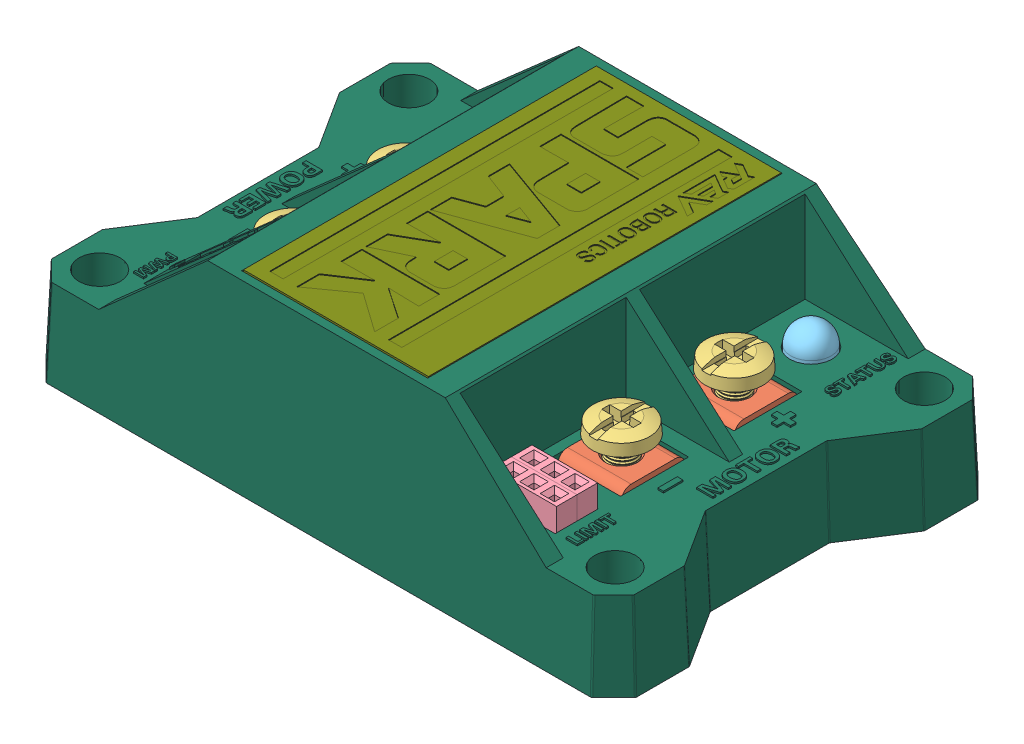
SolidWorks assembly REV-11-1200, configuration Default. Lengths in mm.
Overall size (73.01 27.38 47.86).
37 component instances, 17 part files, 0 mates.
Components (placement in the parent):
- REV_SPARK-1: REV_SPARK [Default] at (-30.2194 -29.0303 -50.3438) size (73.01 27.38 47.86)
  - RR-SPARK-BD-B-Assembly-1: RR-SPARK-BD-B-Assembly [Default] at (2.3249 6.4587 12.2534) size (55.12 26.11 42.42)
    - RR-SPARK-BD-B-1: RR-SPARK-BD-B [Default] at (27.8945 25.8332 38.0904) size (53.34 3.8 40.64)
    - ScrewTerminalAssembly-1: ScrewTerminalAssembly [Default] at (15.7541 22.7195 39.4261) x (0 0 1) z (-1 0 0) size (7.87 11.69 7.87)
      - ScrewTerminalBase-1: ScrewTerminalBase [Default] at (3.4868 6.6312 8.3972) size (7.87 7.68 7.87)
      - ScrewTerminalScrew-1: ScrewTerminalScrew [Default] at (3.5041 -1.1314 8.5263) x (0.998152 0 -0.060771) z (0.060771 0 0.998152) size (7.16 8.3 7.16)
    - ScrewTerminalAssembly-2: ScrewTerminalAssembly [Default] at (56.3941 22.7195 39.4261) x (0 0 1) z (-1 0 0) size (7.87 11.69 7.87)
      - ScrewTerminalBase-1: ScrewTerminalBase [Default] at (3.4868 6.6312 8.3972) size (7.87 7.68 7.87)
      - ScrewTerminalScrew-1: ScrewTerminalScrew [Default] at (3.5041 -1.1314 8.5263) x (0.998152 0 -0.060771) z (0.060771 0 0.998152) size (7.16 8.3 7.16)
    - ScrewTerminalAssembly-3: ScrewTerminalAssembly [Default] at (15.7541 22.7195 25.4561) x (0 0 1) z (-1 0 0) size (7.87 11.69 7.87)
      - ScrewTerminalBase-1: ScrewTerminalBase [Default] at (3.4868 6.6312 8.3972) size (7.87 7.68 7.87)
      - ScrewTerminalScrew-1: ScrewTerminalScrew [Default] at (3.5041 -1.1314 8.5263) x (0.998152 0 -0.060771) z (0.060771 0 0.998152) size (7.16 8.3 7.16)
    - ScrewTerminalAssembly-4: ScrewTerminalAssembly [Default] at (56.3941 22.7195 25.4561) x (0 0 1) z (-1 0 0) size (7.87 11.69 7.87)
      - ScrewTerminalBase-1: ScrewTerminalBase [Default] at (3.4868 6.6312 8.3972) size (7.87 7.68 7.87)
      - ScrewTerminalScrew-1: ScrewTerminalScrew [Default] at (3.5041 -1.1314 8.5263) x (0.998152 0 -0.060771) z (0.060771 0 0.998152) size (7.16 8.3 7.16)
    - Header-Female-1x3-PPTC031LFBN-RC-1: Header-Female-1x3-PPTC031LFBN-RC [Default] at (7.5745 27.4332 53.3304) size (8.13 15.71 2.54)
    - Header-Female-1x3-PPTC031LFBN-RC-2: Header-Female-1x3-PPTC031LFBN-RC [Default] at (48.2145 27.4332 53.3304) size (8.13 15.71 2.54)
    - Header-Female-1x3-PPTC031LFBN-RC-3: Header-Female-1x3-PPTC031LFBN-RC [Default] at (48.2145 27.4332 55.8704) size (8.13 15.71 2.54)
    - LED-RGB-ThroughHole-1: LED-RGB-ThroughHole [Default] at (48.2145 27.4332 21.5804) x (-1 0 0) z (0 0 -1) size (5.45 12.2 5.9)
    - MOSFET-PSMN1R0-30YLC115-1: MOSFET-PSMN1R0-30YLC115 [Default] at (35.6415 27.4332 27.2954) x (0 0 -1) z (1 0 0) size (5 1.2 6.72)
    - MOSFET-PSMN1R0-30YLC115-2: MOSFET-PSMN1R0-30YLC115 [Default] at (36.5305 27.4332 33.6454) size (5 1.2 6.72)
    - MOSFET-PSMN1R0-30YLC115-3: MOSFET-PSMN1R0-30YLC115 [Default] at (36.5305 27.4332 42.5354) x (-1 0 0) z (0 0 -1) size (5 1.2 6.72)
    - MOSFET-PSMN1R0-30YLC115-4: MOSFET-PSMN1R0-30YLC115 [Default] at (35.6415 27.4332 48.8854) x (0 0 -1) z (1 0 0) size (5 1.2 6.72)
    - Varistor-1: Varistor [Default] at (52.6595 27.4332 22.5964) x (0 0 1) z (-1 0 0) size (3.4 1.02 1.45)
    - Varistor-2: Varistor [Default] at (41.2295 27.4332 53.7114) x (0 0 1) z (-1 0 0) size (3.4 1.02 1.45)
    - Crystal-1: Crystal [Default] at (17.9885 27.4332 48.3774) x (0 0 1) z (-1 0 0) size (5.2 1.5 3.4)
    - Button-PTS645SM43SMTR92LFS-1: Button-PTS645SM43SMTR92LFS [Default] at (8.0825 27.4332 21.5804) size (9 4.3 6)
    - OptoIsolator-TLP118-1: OptoIsolator-TLP118 [Default] at (14.1785 27.4332 50.4094) x (0 0 -1) z (1 0 0) size (7.02 2.2 3.7)
    - GateDriver-A4940KLPTR-T-1: GateDriver-A4940KLPTR-T [Default] at (30.1805 25.8332 53.9654) x (0 0 -1) z (-1 0 0) size (7.8 1.2 6.43)
    - MCU-PIC16F1828-I-GZ-1: MCU-PIC16F1828-I-GZ [Default] at (19.0045 25.8332 52.8224) x (-1 0 0) z (0 0 1) size (4 0.55 4)
    - Capacitor-UCL1V471MNL1GS-1: Capacitor-UCL1V471MNL1GS [Default] at (25.8625 27.4332 46.5994) x (0 0 1) z (-1 0 0) size (10.5 14.3 11.5)
    - Capacitor-UCL1V471MNL1GS-2: Capacitor-UCL1V471MNL1GS [Default] at (25.8625 27.4332 25.2634) x (0 0 1) z (-1 0 0) size (10.5 14.3 11.5)
    - Capacitor-UCL1V471MNL1GS-3: Capacitor-UCL1V471MNL1GS [Default] at (25.8625 27.4332 35.9314) x (0 0 -1) z (1 0 0) size (10.5 14.3 11.5)
    - 1mmborder-1: 1mmborder [Default] at (27.8945 25.8332 38.0904) size (55.12 1.6 42.42)
  - Spark_P01-REV-41_TOPSHELL-1: Spark_P01-REV-41_TOPSHELL [Default] at (30.1178 29.0303 87.4264) x (1 0 0) z (0 1 0) size (73.01 47.86 22.14)
  - heatsink-1: heatsink [Default] at (29.9048 43.475 28.4732) size (25.78 15.52 43.69)
  - Spark_P01-REV-41_bottom_cover-1: Spark_P01-REV-41_bottom_cover [Default] at (30.1178 29.0303 87.4264) x (1 0 0) z (0 -1 0) size (65.7 43.71 2.65)
